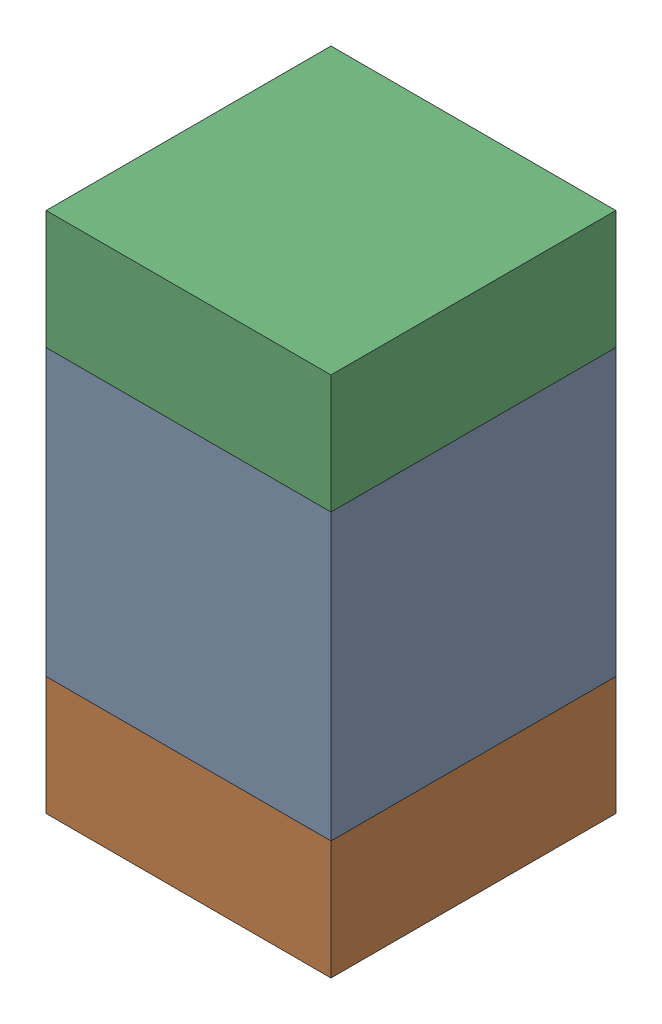
SolidWorks assembly C600_1PCB, configuration Default. Lengths in mm.
Overall size (0.6 1.1 0.6).
6 component instances, 2 part files, 0 mates.
Components (placement in the parent):
- 761606048-1: 761606048 [Default] at (100.7 110.6 -2.2638) size (0.6 0.6 0.6)
  - Extruded_9-1: Extruded_9 [Default] at origin size (0.6 0.6 0.6)
- 854785296-1: 854785296 [Default] at (100.7 110.175 -2.2638) size (0.6 0.25 0.6)
  - Extruded_10-1: Extruded_10 [Default] at origin size (0.6 0.25 0.6)
- 854785296-2: 854785296 [Default] at (100.7 111.025 -2.2638) size (0.6 0.25 0.6)
  - Extruded_10-1: Extruded_10 [Default] at origin size (0.6 0.25 0.6)
